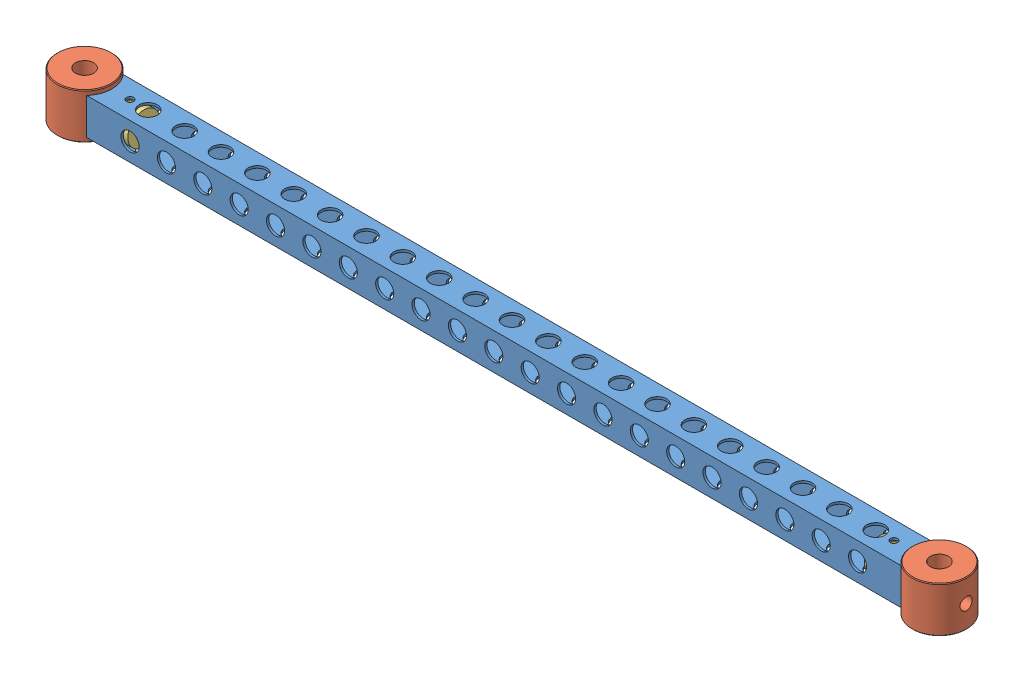
SolidWorks assembly Assem1, configuration Default. Lengths in mm.
Overall size (635 31.75 38.1).
5 component instances, 3 part files, 8 mates.
Components (placement in the parent):
- Link Short-1: Link Short [Default] at origin size (568.5 25.4 25.4)
- End-1: End [Default] at (596.9 28.575 -12.7) x (0 -1 0) z (1 0 0) size (31.75 38.1 38.1)
- End-2: End [Default] at (0 -3.175 -12.7) x (0 1 0) z (-1 0 0) size (31.75 38.1 38.1)
- End Interlock-1: End Interlock [Default] at (577.85 12.7 -12.7) x (0 0 -1) z (1 0 0) size (22.23 22.23 22.23)
- End Interlock-2: End Interlock [Default] at (19.05 12.7 -12.7) x (0 0 1) z (-1 0 0) size (22.23 22.23 22.23)
Mates (geometry in assembly coordinates):
- Concentric2: concentric aligned: circle of End-2; circle of End Interlock-2
- Tangent3: tangent anti-aligned: cylinder of End-2 through (0 28.575 -12.7) axis (0 -1 0) radius 19.05; plane of End Interlock-2 through (19.05 12.7 -12.7) normal (-1 0 0)
- Concentric3: concentric anti-aligned: circle of Link Short-1; cylinder of End Interlock-2 through (31.75 12.7 -12.7) axis (0 -1 0) radius 1.8986
- Tangent5: tangent anti-aligned: plane of Link Short-1 through (596.9 23.8125 -1.5875) normal (0 -1 0); cylinder of End Interlock-2 through (41.275 12.7 -12.7) axis (-1 0 0) radius 11.1125
- Concentric4: concentric aligned: cylinder of End-1 through (577.85 12.7 -12.7) axis (1 0 0) radius 2.5; cylinder of End Interlock-1 through (577.85 12.7 -12.7) axis (1 0 0) radius 1.8986
- Tangent6: tangent anti-aligned: cylinder of End-1 through (596.9 -3.175 -12.7) axis (0 1 0) radius 19.05; plane of End Interlock-1 through (577.85 12.7 -12.7) normal (1 0 0)
- Concentric5: concentric anti-aligned: circle of Link Short-1; cylinder of End Interlock-1 through (565.15 12.7 -12.7) axis (0 -1 0) radius 1.8986
- Tangent7: tangent anti-aligned: plane of Link Short-1 through (596.9 23.8125 -1.5875) normal (0 -1 0); cylinder of End Interlock-1 through (555.625 12.7 -12.7) axis (1 0 0) radius 11.1125
